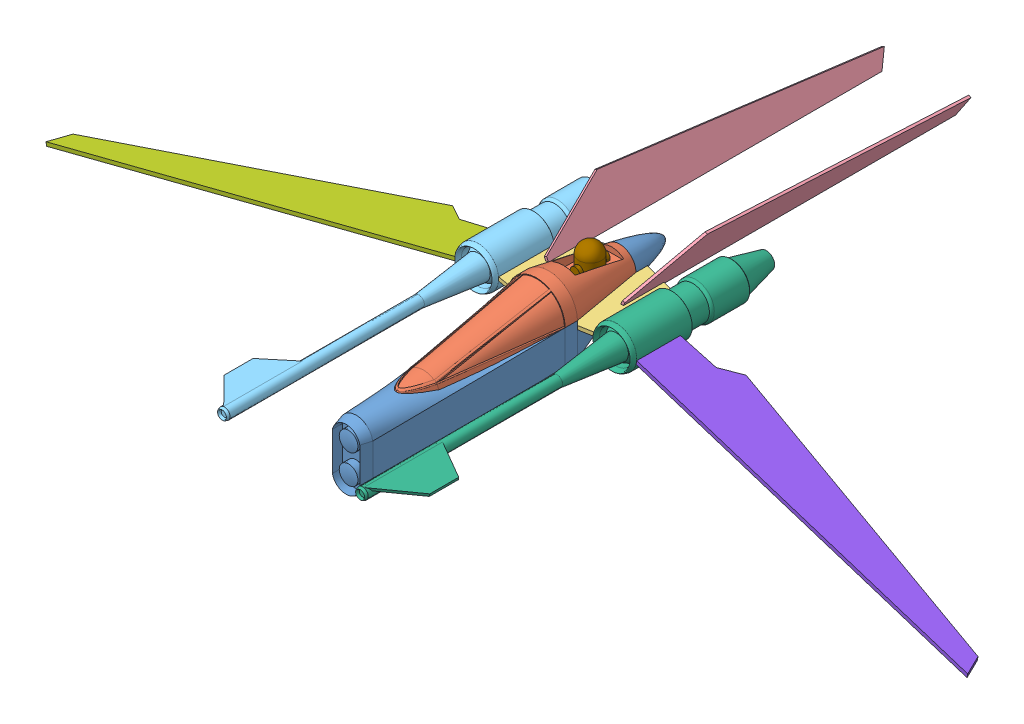
SolidWorks assembly Vector_Assembly, configuration Default. Lengths in mm.
Overall size (18677.78 2249.18 12876.08).
10 component instances, 9 part files, 12 mates.
Components (placement in the parent):
- Vector_Fuselage-1: Vector_Fuselage [Default] at origin size (1170.07 1682.83 6442.75)
- Vector_Canopy-2: Vector_Canopy [Default] at (0 0 -2696.6869) size (1170.04 685.01 4564.34)
- Vector_Connecting_Wing-1: Vector_Connecting_Wing [Default] at (0.134 -75 -4325.5427) x (1 0 0) z (0 0 1) size (1966.12 75 1759.28)
- Vector_Tailwing-1: Vector_Tailwing [Default] at (-723.4692 -19.3483 -4335.6488) x (0 0 1) z (0.422618 -0.906308 0) size (6930 50 877.5)
- Vector_Tailwing-3: Vector_Tailwing [Default] at (768.7845 -40.4792 -4335.6488) x (0 0 1) z (-0.422618 -0.906308 0) size (6930 50 877.5)
- Vector_Engine-9: Vector_Engine [Default] at (-1399.3125 -37.5 -3577.0741) x (0.984808 0.173648 0) z (0 0 1) size (1089.48 832.5 8230.5)
- Vector_Engine_Right-5: Vector_Engine_Right [Default] at (1399.312 -37.5 -3577.0738) x (0.984808 -0.173648 0) z (0 0 1) size (1093.02 832.5 8230.5)
- Vector_Wing-5: Vector_Wing [Default] at (-1903.29 -164.4433 -3566.1612) x (0.984808 0.173648 0) z (0 0 1) size (7639.2 75 1873.8)
- Vector_Wing_Right-4: Vector_Wing_Right [Default] at (1702.1633 -128.9793 -3566.1609) x (0.984808 -0.173648 0) z (0 0 1) size (7639.2 75 1873.8)
- astromech-1: astromech [Default] at (0 -404.6568 -4447.9376) size (461.74 1090 611.74)
Mates (geometry in assembly coordinates):
- Coincident1: coincident: point of Vector_Fuselage-1; point of Vector_Canopy-2
- Coincident3: coincident: point of Vector_Fuselage-1; point of Vector_Connecting_Wing-1
- Coincident21: coincident: unknown of Vector_Connecting_Wing-1
- Coincident22: coincident: unknown of Vector_Connecting_Wing-1
- Coincident23: coincident: line of Vector_Connecting_Wing-1 through (-983.0625 0 -3577.0741) axis (0 -1 0)
- Coincident24: coincident: unknown of Vector_Connecting_Wing-1
- Coincident25: coincident: unknown of Vector_Connecting_Wing-1
- Coincident28: coincident: circle of Vector_Engine-9; moEndPointRef_w of Vector_Wing-4
- Coincident31: coincident: point of assembly; point of Vector_Engine-9; point of Vector_Wing-5
- Coincident32: coincident: point of assembly; point of Vector_Engine-9; point of Vector_Wing-5
- Coincident33: coincident: point of assembly; point of Vector_Engine_Right-5; point of Vector_Wing_Right-4
- Coincident34: coincident: point of assembly; point of Vector_Engine_Right-5; point of Vector_Wing_Right-4
